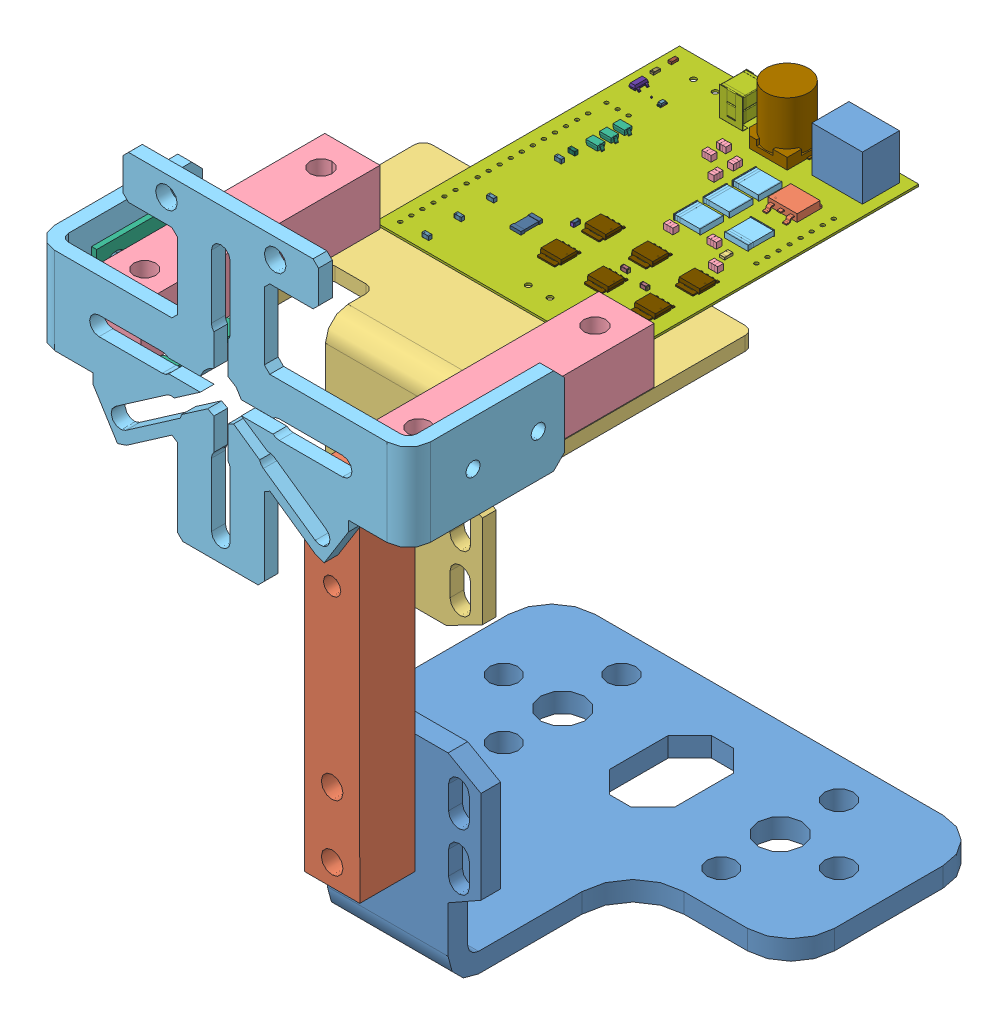
SolidWorks assembly static_test_setup_assembly, configuration Default. Lengths in mm.
Overall size (100 169.24 133.11).
143 component instances, 33 part files, 18 mates.
Components (placement in the parent):
- stress_test_base2-1: stress_test_base2 [Default] at (0.326 -26.3998 90.47) size (100 47.5 90)
- load_cells_long-1: load_cells_long [Default] at (-6.3194 -6.3175 87.97) x (1 0.000118 0) z (0 0 1) size (12.7 80 12.7)
- static_test_upper_support_plate-1: static_test_upper_support_plate [Default] at (-38.33 93.7587 91.3569) x (1 0.000118 0) z (0 0 1) size (76 47.5 50)
- load_cell_small-1: load_cell_small [Default] at (-38.1716 93.7588 119.1415) x (1 0.000118 -0.000148) z (0.000148 0 1) size (12.7 12.7 55)
- load_cell_small-2: load_cell_small [Default] at (24.8184 93.7662 119.1322) x (1 0.000118 -0.000148) z (0.000148 0 1) size (12.7 12.7 55)
- static_test_motor_mount2-1: static_test_motor_mount2 [Default] at (0.6278 104.9092 123.6809) x (1 0.000118 -0.000148) z (0.000148 0 1) size (86.36 71.25 35.82)
- hinges-1: hinges [Default] at (-39.3718 92.5586 116.5874) x (1 0.000118 -0.000148) z (0.000148 0 1) size (17.88 17 24)
- hinges-2: hinges [Default] at (40.6246 92.5808 92.5528) x (-1 -0.000118 0.000148) z (-0.000148 0 -1) size (17.88 17 24)
- PCB4-1: PCB4 [Default] at (-103.2249 94.2337 -57.0424) x (0 0 1) z (-0.000118 1 0) size (70 55 17.74)
  - PCB4.step-1: PCB4.step [Default] at origin size (70 55 17.74)
    - Board.step-1: Board.step [Default] at origin size (70 55 0.48)
      - Open CASCADE STEP translator 6.8 1.1.1.step-1: Open CASCADE STEP translator 6.8 1.1.1.step [Default] at (0 0 -0.4826) size (70 55 0.48)
    - C11.step-1: C11.step [Default] at origin size (10.31 11.2 12.76)
      - 8436813712.step-1: 8436813712.step [Default] at (57.912 108.331 0) size (0.25 0.25 0.25)
        - Extruded.step-1: Extruded.step [Default] at origin size (0.25 0.25 0.25)
      - CAP_PC_10X12P7_NCH.step-1: CAP_PC_10X12P7_NCH.step [Default] at (58.0389 108.2041 0) x (0 1 0) z (0 0 1) size (11.2 10.31 12.76)
    - R10.step-1: R10.step [Default] at origin size (5 2.5 0.71)
      - 8436813712.step-1: 8436813712.step [Default] at (104.078 94.283 0) size (0.25 0.25 0.25)
        - Extruded.step-1: Extruded.step [Default] at origin size (0.25 0.25 0.25)
      - RC2010N_VIS.step-1: RC2010N_VIS.step [Default] at (104.2049 94.4099 0) x (-1 0 0) z (0 0 1) size (5 2.5 0.71)
    - R_PWR.step-1: R_PWR.step [Default] at origin size (1.6 0.8 0.55)
      - CR0603-JW-821ELF.step-1: CR0603-JW-821ELF.step [Default] at (54.67 78.65 0) x (1 0 0) z (0 -1 0) size (1.6 0.55 0.8)
    - PWR.step-1: PWR.step [Default] at origin size (0.25 0.25 0.25)
      - 8436813712.step-1: 8436813712.step [Default] at (64.343 83.318 0) size (0.25 0.25 0.25)
        - Extruded.step-1: Extruded.step [Default] at origin size (0.25 0.25 0.25)
    - G_R_LED.step-1: G_R_LED.step [Default] at origin size (1.6 0.8 0.55)
      - RK73H1JTTD6490F.step-1: RK73H1JTTD6490F.step [Default] at (58.83 78.68 0) x (1 0 0) z (0 -1 0) size (1.6 0.55 0.8)
    - GATE_ON.step-1: GATE_ON.step [Default] at origin size (1.6 0.8 0.7)
      - 150060AS75000_STP_150060xS75000_rev1.step-1: 150060AS75000_STP_150060xS75000_rev1.step [Default] at (64.5449 85.9399 0) x (-1 0 0) z (0 0 1) size (1.6 0.8 0.7)
        - housing.step-1: housing.step [Default] at origin size (1.6 0.8 0.3)
        - cover.step-1: cover.step [Default] at (0 0 0.3) size (1.1 0.8 0.4)
        - base.step-1: base.step [Default] at (-0.675 0 0) size (0.45 0.8 0.3)
        - base.step-2: base.step [Default] at (0.675 0 0) x (-1 0 0) z (0 0 1) size (0.45 0.8 0.3)
        - Polarity_Mark.step-1: Polarity_Mark.step [Default] at (-0.675 0.35 0.3) size (0.25 0.1 0)
    - G_LED_FET.step-1: G_LED_FET.step [Default] at origin size (3.05 2.51 1.14)
      - 8436813712.step-1: 8436813712.step [Default] at (63.403 79.403 0) size (0.25 0.25 0.25)
        - Extruded.step-1: Extruded.step [Default] at origin size (0.25 0.25 0.25)
      - TO-236AB_NEX.step-1: TO-236AB_NEX.step [Default] at (63.5299 79.5299 0) x (-1 0 0) z (0 0 1) size (3.05 2.51 1.14)
    - T6.step-1: T6.step [Default] at origin size (6 4.9 1.2)
      - 8639367424.step-1: 8639367424.step [Default] at (96.322 104.123 0) x (0 -1 0) z (-1 0 0) size (4.9 1.2 6)
    - T5.step-1: T5.step [Default] at origin size (6 4.9 1.2)
      - 8639367424.step-1: 8639367424.step [Default] at (96.322 114.918 0) x (0 -1 0) z (-1 0 0) size (4.9 1.2 6)
    - T4.step-1: T4.step [Default] at origin size (6 4.9 1.2)
      - 8639367424.step-1: 8639367424.step [Default] at (96.322 125.713 0) x (0 -1 0) z (-1 0 0) size (4.9 1.2 6)
    - T3.step-1: T3.step [Default] at origin size (6 4.9 1.2)
      - 8639367424.step-1: 8639367424.step [Default] at (106.4166 104.02 0) x (0 -1 0) z (-1 0 0) size (4.9 1.2 6)
    - T2.step-1: T2.step [Default] at origin size (6 4.9 1.2)
      - 8639367424.step-1: 8639367424.step [Default] at (106.4166 114.815 0) x (0 -1 0) z (-1 0 0) size (4.9 1.2 6)
    - T1.step-1: T1.step [Default] at origin size (6 4.9 1.2)
      - 8639367424.step-1: 8639367424.step [Default] at (106.4166 125.61 0) x (0 -1 0) z (-1 0 0) size (4.9 1.2 6)
    - U3.step-1: U3.step [Default] at origin size (8.51 11.61 15.37)
      - 8436813712.step-1: 8436813712.step [Default] at (59.055 120.65 0) size (0.25 0.25 0.25)
        - Extruded.step-1: Extruded.step [Default] at origin size (0.25 0.25 0.25)
      - R-78E50-05_RCP.step-1: R-78E50-05_RCP.step [Default] at (57.023 120.3961 0) x (0 1 0) z (0 0 1) size (11.61 8.51 15.37)
    - U2.step-1: U2.step [Default] at origin size (8.07 6.75 1.76)
      - 8436813712.step-1: 8436813712.step [Default] at (68.0095 121.602 0) size (0.25 0.25 0.25)
        - Extruded.step-1: Extruded.step [Default] at origin size (0.25 0.25 0.25)
      - DPAK-3_ONS.step-1: DPAK-3_ONS.step [Default] at (69.2795 121.475 0) x (0 1 0) z (0 0 1) size (6.75 8.07 1.76)
    - L1.step-1: L1.step [Default] at origin size (2 1.25 1.05)
      - 8639373664.step-1: 8639373664.step [Default] at (87.255 123.41 0) x (1 0 0) z (0 -1 0) size (2 1.05 1.25)
    - C35.step-1: C35.step [Default] at origin size (1.35 2.11 1.35)
      - 8436813712.step-1: 8436813712.step [Default] at (66.158 102.077 0) size (0.25 0.25 0.25)
        - Extruded.step-1: Extruded.step [Default] at origin size (0.25 0.25 0.25)
      - CAP_GRM_21B_MUR.step-1: CAP_GRM_21B_MUR.step [Default] at (66.2849 101.9501 0) x (0 1 0) z (0 0 1) size (2.11 1.35 1.35)
    - C34.step-1: C34.step [Default] at origin size (5.41 6.1 1.25)
      - 8436813712.step-1: 8436813712.step [Default] at (76.544 113.341 0) size (0.25 0.25 0.25)
        - Extruded.step-1: Extruded.step [Default] at origin size (0.25 0.25 0.25)
      - CAP_5750_TDK.step-1: CAP_5750_TDK.step [Default] at (76.671 113.2141 0) x (0 1 0) z (0 0 1) size (6.1 5.41 1.25)
    - C33.step-1: C33.step [Default] at origin size (1.35 2.11 1.35)
      - 8436813712.step-1: 8436813712.step [Default] at (69.518 102.062 0) size (0.25 0.25 0.25)
        - Extruded.step-1: Extruded.step [Default] at origin size (0.25 0.25 0.25)
      - CAP_GRM_21B_MUR.step-1: CAP_GRM_21B_MUR.step [Default] at (69.6449 101.9351 0) x (0 1 0) z (0 0 1) size (2.11 1.35 1.35)
    - C32.step-1: C32.step [Default] at origin size (1.35 2.11 1.35)
      - 8436813712.step-1: 8436813712.step [Default] at (88.378 112.142 0) size (0.25 0.25 0.25)
        - Extruded.step-1: Extruded.step [Default] at origin size (0.25 0.25 0.25)
      - CAP_GRM_21B_MUR.step-1: CAP_GRM_21B_MUR.step [Default] at (88.5049 112.0151 0) x (0 1 0) z (0 0 1) size (2.11 1.35 1.35)
    - C31.step-1: C31.step [Default] at origin size (5.41 6.1 1.25)
      - 8436813712.step-1: 8436813712.step [Default] at (69.813 113.341 0) size (0.25 0.25 0.25)
        - Extruded.step-1: Extruded.step [Default] at origin size (0.25 0.25 0.25)
      - CAP_5750_TDK.step-1: CAP_5750_TDK.step [Default] at (69.94 113.2141 0) x (0 1 0) z (0 0 1) size (6.1 5.41 1.25)
    - C30.step-1: C30.step [Default] at origin size (2.11 1.35 1.35)
      - 8436813712.step-1: 8436813712.step [Default] at (72.818 106.538 0) size (0.25 0.25 0.25)
        - Extruded.step-1: Extruded.step [Default] at origin size (0.25 0.25 0.25)
      - CAP_GRM_21B_MUR.step-1: CAP_GRM_21B_MUR.step [Default] at (72.9449 106.6649 0) x (-1 0 0) z (0 0 1) size (2.11 1.35 1.35)
    - C29.step-1: C29.step [Default] at origin size (5.41 6.1 1.25)
      - 8436813712.step-1: 8436813712.step [Default] at (83.275 113.341 0) size (0.25 0.25 0.25)
        - Extruded.step-1: Extruded.step [Default] at origin size (0.25 0.25 0.25)
      - CAP_5750_TDK.step-1: CAP_5750_TDK.step [Default] at (83.402 113.2141 0) x (0 1 0) z (0 0 1) size (6.1 5.41 1.25)
    - C28.step-1: C28.step [Default] at origin size (2.11 1.35 1.35)
      - 8436813712.step-1: 8436813712.step [Default] at (68.622 106.792 0) size (0.25 0.25 0.25)
        - Extruded.step-1: Extruded.step [Default] at origin size (0.25 0.25 0.25)
      - CAP_GRM_21B_MUR.step-1: CAP_GRM_21B_MUR.step [Default] at (68.4951 106.6651 0) x (1 0 0) z (0 0 1) size (2.11 1.35 1.35)
    - C27.step-1: C27.step [Default] at origin size (1.35 2.11 1.35)
      - 8436813712.step-1: 8436813712.step [Default] at (86.243 119.997 0) size (0.25 0.25 0.25)
        - Extruded.step-1: Extruded.step [Default] at origin size (0.25 0.25 0.25)
      - CAP_GRM_21B_MUR.step-1: CAP_GRM_21B_MUR.step [Default] at (86.3699 119.8701 0) x (0 1 0) z (0 0 1) size (2.11 1.35 1.35)
    - C26.step-1: C26.step [Default] at origin size (1.35 2.11 1.35)
      - 8436813712.step-1: 8436813712.step [Default] at (90.932 124.968 0) size (0.25 0.25 0.25)
        - Extruded.step-1: Extruded.step [Default] at origin size (0.25 0.25 0.25)
      - CAP_GRM_21B_MUR.step-1: CAP_GRM_21B_MUR.step [Default] at (91.0589 124.8411 0) x (0 1 0) z (0 0 1) size (2.11 1.35 1.35)
    - C25.step-1: C25.step [Default] at origin size (6.1 5.41 1.25)
      - 8436813712.step-1: 8436813712.step [Default] at (80.648 122.158 0) size (0.25 0.25 0.25)
        - Extruded.step-1: Extruded.step [Default] at origin size (0.25 0.25 0.25)
      - CAP_5750_TDK.step-1: CAP_5750_TDK.step [Default] at (80.7749 122.285 0) x (-1 0 0) z (0 0 1) size (6.1 5.41 1.25)
    - D5.step-1: D5.step [Default] at origin size (1.72 3.61 1.21)
      - 8436813712.step-1: 8436813712.step [Default] at (74.382 86.408 0) size (0.25 0.25 0.25)
        - Extruded.step-1: Extruded.step [Default] at origin size (0.25 0.25 0.25)
      - SOD123F_NXP.step-1: SOD123F_NXP.step [Default] at (74.2551 86.5349 0) x (0 -1 0) z (0 0 1) size (3.61 1.72 1.21)
    - D4.step-1: D4.step [Default] at origin size (1.72 3.61 1.21)
      - 8436813712.step-1: 8436813712.step [Default] at (77.452 86.408 0) size (0.25 0.25 0.25)
        - Extruded.step-1: Extruded.step [Default] at origin size (0.25 0.25 0.25)
      - SOD123F_NXP.step-1: SOD123F_NXP.step [Default] at (77.3251 86.5349 0) x (0 -1 0) z (0 0 1) size (3.61 1.72 1.21)
    - D3.step-1: D3.step [Default] at origin size (1.72 3.61 1.21)
      - 8436813712.step-1: 8436813712.step [Default] at (80.602 86.408 0) size (0.25 0.25 0.25)
        - Extruded.step-1: Extruded.step [Default] at origin size (0.25 0.25 0.25)
      - SOD123F_NXP.step-1: SOD123F_NXP.step [Default] at (80.4751 86.5348 0) x (0 -1 0) z (0 0 1) size (3.61 1.72 1.21)
    - C15.step-1: C15.step [Default] at origin size (6.1 5.3 6.7)
      - 8639373424.step-1: 8639373424.step [Default] at (57.468 97.79 0) x (1 0 0) z (0 -1 0) size (6.1 6.7 5.3)
    - C14.step-1: C14.step [Default] at origin size (1.6 0.8 0.9)
      - 8639369904.step-1: 8639369904.step [Default] at (98.38 99.905 0) x (-1 0 0) z (0 0 1) size (1.6 0.8 0.9)
        - Fillet1.step-1: Fillet1.step [Default] at origin size (0.2 0.8 0.9)
        - Fillet2.step-1: Fillet2.step [Default] at origin size (0.2 0.8 0.9)
        - body2.step-1: body2.step [Default] at origin size (1.2 0.78 0.88)
    - C13.step-1: C13.step [Default] at origin size (0.8 1.6 0.9)
      - 7937347552.step-1: 7937347552.step [Default] at (101.855 114.86 0) x (0 1 0) z (0 0 1) size (1.6 0.8 0.9)
        - Fillet1-0.step-1: Fillet1-0.step [Default] at origin size (0.2 0.8 0.9)
        - Fillet2-1.step-1: Fillet2-1.step [Default] at origin size (0.2 0.8 0.9)
        - body2-2.step-1: body2-2.step [Default] at origin size (1.2 0.78 0.88)
    - C12.step-1: C12.step [Default] at origin size (0.8 1.6 0.9)
      - 7937347552.step-1: 7937347552.step [Default] at (103.08 120.51 0) x (0 1 0) z (0 0 1) size (1.6 0.8 0.9)
        - Fillet1-0.step-1: Fillet1-0.step [Default] at origin size (0.2 0.8 0.9)
        - Fillet2-1.step-1: Fillet2-1.step [Default] at origin size (0.2 0.8 0.9)
        - body2-2.step-1: body2-2.step [Default] at origin size (1.2 0.78 0.88)
    - C10.step-1: C10.step [Default] at origin size (0.81 1.6 0.9)
      - 8639369984.step-1: 8639369984.step [Default] at (118.015 85.345 0) x (0 -1 0) z (-1 0 0) size (1.6 0.9 0.81)
    - C8.step-1: C8.step [Default] at origin size (0.81 1.6 0.9)
      - 8639369984.step-1: 8639369984.step [Default] at (110.5485 85.345 0) x (0 -1 0) z (-1 0 0) size (1.6 0.9 0.81)
    - C6.step-1: C6.step [Default] at origin size (0.81 1.6 0.9)
      - 8639369984.step-1: 8639369984.step [Default] at (103.082 85.345 0) x (0 -1 0) z (-1 0 0) size (1.6 0.9 0.81)
    - C2.step-1: C2.step [Default] at origin size (0.81 1.6 0.9)
      - 8639369984.step-1: 8639369984.step [Default] at (87.52 85.345 0) x (0 -1 0) z (-1 0 0) size (1.6 0.9 0.81)
    - C1.step-1: C1.step [Default] at origin size (0.81 1.6 0.9)
      - 7937352272.step-1: 7937352272.step [Default] at (84.4157 85.345 0) x (0 1 0) z (1 0 0) size (1.6 0.9 0.81)
Mates (geometry in assembly coordinates):
- Coincident7: coincident anti-aligned: plane of static_test_upper_support_plate-1 through (-38.33 93.7587 91.3569) normal (-0.000118 1 0); plane of load_cell_small-1 through (-38.1716 93.7588 119.1415) normal (0.000118 -1 0)
- Coincident8: coincident anti-aligned: plane of static_test_upper_support_plate-1 through (-38.33 93.7587 91.3569) normal (-0.000118 1 0); plane of load_cell_small-2 through (24.8184 93.7662 119.1322) normal (0.000118 -1 0)
- Coincident10: coincident aligned: plane of load_cell_small-1 through (-25.4731 106.4603 119.1396) normal (0.000148 0 1); plane of load_cell_small-2 through (37.5169 106.4677 119.1303) normal (0.000148 0 1)
- Lock1: lock: unknown of load_cell_small-1; unknown of load_cell_small-2
- Coincident21: coincident anti-aligned: plane of stress_test_base2-1 through (-11.2718 18.6002 87.97) normal (0 0 1); plane of load_cells_long-1 through (-6.3194 -6.3175 87.97) normal (0 0 -1)
- Concentric1: concentric aligned: circle of load_cells_long-1; circle of static_test_upper_support_plate-1
- Concentric6: concentric anti-aligned: cylinder of load_cells_long-1; cylinder of static_test_upper_support_plate-1 through (0.0217 68.6833 87.97) axis (0 0 -1) radius 3.25
- Concentric7: concentric aligned: circle of stress_test_base2-1; circle of load_cells_long-1
- Coincident27: coincident anti-aligned: plane of static_test_motor_mount2-1 through (-39.3722 104.9045 123.6868) normal (1 0.000118 -0.000148); plane of hinges-1 through (-39.3718 92.5586 116.5874) normal (-1 -0.000118 0.000148)
- Concentric8: concentric aligned: circle of static_test_motor_mount2-1; circle of hinges-1
- Concentric9: concentric aligned: circle of static_test_motor_mount2-1; circle of hinges-1
- Coincident28: coincident anti-aligned: plane of load_cell_small-1 through (-38.1716 93.7588 119.1415) normal (0.000118 -1 0); plane of hinges-1 through (-39.372 93.7586 116.5874) normal (-0.000118 1 0)
- Coincident36: coincident anti-aligned: plane of load_cell_small-1 through (-38.1731 106.4588 119.1415) normal (-1 -0.000118 0.000148); plane of hinges-1 through (-38.1718 92.5588 116.5872) normal (1 0.000118 -0.000148)
- Coincident38: coincident anti-aligned: plane of static_test_motor_mount2-1 through (40.6278 104.914 123.675) normal (-1 -0.000118 0.000148); plane of hinges-2 through (40.6246 92.5808 92.5528) normal (1 0.000118 -0.000148)
- Concentric11: concentric anti-aligned: circle of static_test_motor_mount2-1; circle of hinges-2
- Concentric12: concentric anti-aligned: circle of static_test_motor_mount2-1; circle of hinges-2
- Parallel4: parallel anti-aligned: plane of static_test_upper_support_plate-1 through (-38.33 93.7587 91.3569) normal (-0.000118 1 0); plane of PCB4-1/PCB4.step-1/Board.step-1/Open CASCADE STEP translator 6.8 1.1.1.step-1 through (-27.0249 93.7601 -6.2424) normal (0.000118 -1 0)
- Coincident42: coincident anti-aligned: plane of static_test_upper_support_plate-1 through (-38.33 93.7587 91.3569) normal (-0.000118 1 0); plane of PCB4-1/PCB4.step-1/Board.step-1/Open CASCADE STEP translator 6.8 1.1.1.step-1 through (-27.0249 93.7601 -6.2424) normal (0.000118 -1 0)
